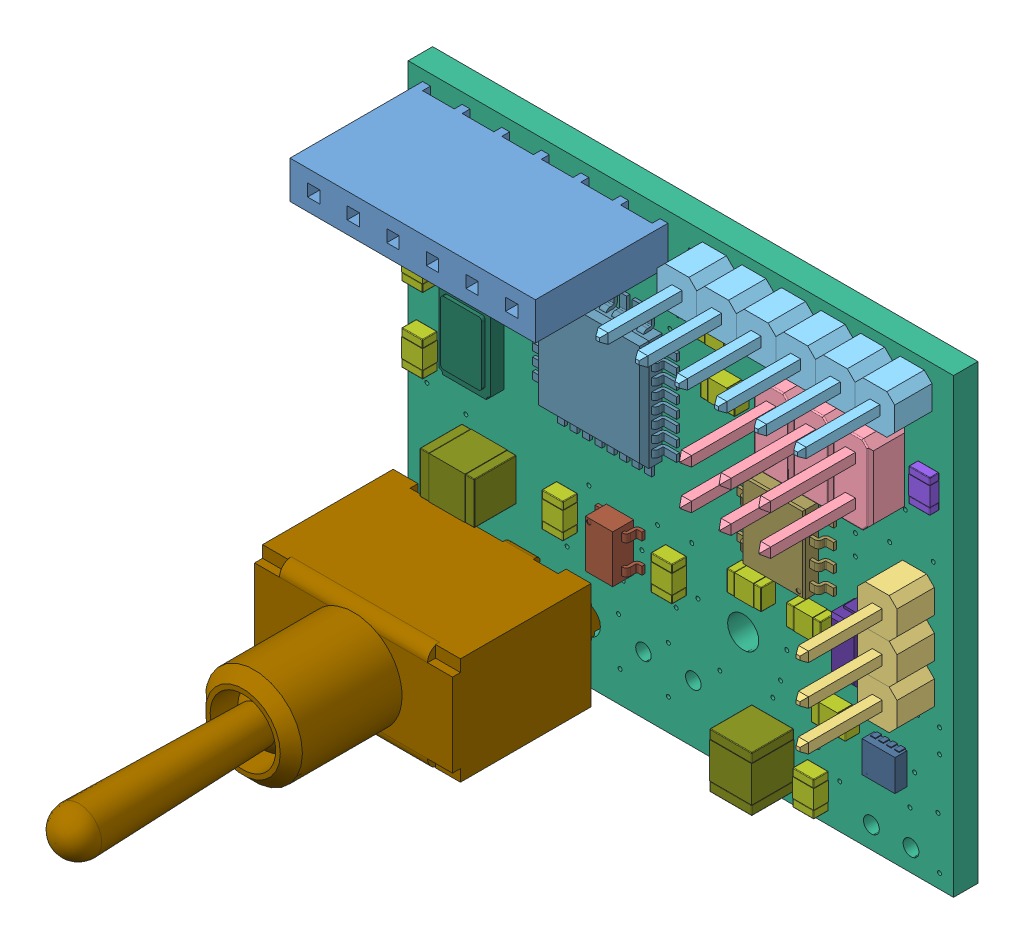
SolidWorks assembly vehicle.step, configuration Default. Lengths in mm.
Overall size (35 29 34.79).
43 component instances, 17 part files, 0 mates.
Components (placement in the parent):
- PCB Component.step-1: PCB Component.step [Default] at origin size (35 29 34.79)
  - HM-10.step-1: HM-10.step [Default] at (8.8 27.1 1.57) x (0 1 0) z (0 0 1) size (2.41 15.75 11.15)
    - _SSW-106-01-S-S_terminal.step-1: _SSW-106-01-S-S_terminal.step [Default] x (0 -1 0) z (-1 0 0) size (15.75 8.51 2.41)
    - _SSW-106-01-S-S_pin.step-1: _SSW-106-01-S-S_pin.step [Default] at (0 0 -2.6416) x (0 -1 0) z (-1 0 0) size (13.74 3.66 1.22)
  - MG90S.step-1: MG90S.step [Default] at (32.5 13.3 1.57) x (0 -1 0) z (0 0 1) size (7.62 2.54 10.67)
    - P(B,C)C01SAAN (1).step-1: P(B,C)C01SAAN (1).step [Default] at (-2.54 0 0) x (1 0 0) z (0 -1 0) size (2.54 10.67 2.54)
    - P(B,C)C01SAAN (1).step-2: P(B,C)C01SAAN (1).step [Default] x (-1 0 0) z (0 1 0) size (2.54 10.67 2.54)
    - P(B,C)C01SAAN (1).step-3: P(B,C)C01SAAN (1).step [Default] at (2.54 0 0) x (1 0 0) z (0 -1 0) size (2.54 10.67 2.54)
  - AVRISP.step-1: AVRISP.step [Default] at (28.2 22.4 1.57) size (7.62 5.08 11.29)
    - Dual TH withbump format.step-1: Dual TH withbump format.step [Default] at (-2.5 0 0) x (1 0 0) z (0 -1 0) size (2.54 11.29 5.08)
    - Dual TH withbump format.step-2: Dual TH withbump format.step [Default] at (0.04 0 0) x (-1 0 0) z (0 1 0) size (2.54 11.29 5.08)
    - Dual TH withbump format.step-3: Dual TH withbump format.step [Default] at (2.58 0 0) x (1 0 0) z (0 -1 0) size (2.54 11.29 5.08)
  - FTDI.step-1: FTDI.step [Default] at (26 27.1 1.57) size (15.24 2.54 10.67)
    - P(B,C)C01SAAN.step-1: P(B,C)C01SAAN.step [Default] at (-6.35 0 0) x (1 0 0) z (0 -1 0) size (2.54 10.67 2.54)
    - P(B,C)C01SAAN.step-2: P(B,C)C01SAAN.step [Default] at (-3.81 0 0) x (-1 0 0) z (0 1 0) size (2.54 10.67 2.54)
    - P(B,C)C01SAAN.step-3: P(B,C)C01SAAN.step [Default] at (-1.27 0 0) x (1 0 0) z (0 -1 0) size (2.54 10.67 2.54)
    - P(B,C)C01SAAN.step-4: P(B,C)C01SAAN.step [Default] at (1.27 0 0) x (-1 0 0) z (0 1 0) size (2.54 10.67 2.54)
    - P(B,C)C01SAAN.step-5: P(B,C)C01SAAN.step [Default] at (3.81 0 0) x (1 0 0) z (0 -1 0) size (2.54 10.67 2.54)
    - P(B,C)C01SAAN.step-6: P(B,C)C01SAAN.step [Default] at (6.35 0 0) x (-1 0 0) z (0 1 0) size (2.54 10.67 2.54)
  - Board.step-1: Board.step [Default] at origin size (35 29 1.57)
  - 1uF_25V.step-1: 1uF_25V.step [Default] at (1.2 13.8 1.57) x (0 -1 0) z (0 0 1) size (2.2 1.35 0.95)
  - 1uF_25V.step-2: 1uF_25V.step [Default] at (20.6 24.4 1.57) size (2.2 1.35 0.95)
  - 1uF_25V.step-3: 1uF_25V.step [Default] at (22.5 11.3 1.57) size (2.2 1.35 0.95)
  - 1uF_25V.step-4: 1uF_25V.step [Default] at (10.2 9.3 1.57) x (0 -1 0) z (0 0 1) size (2.2 1.35 0.95)
  - 1uF_25V.step-5: 1uF_25V.step [Default] at (17.2 9.3 1.57) x (0 -1 0) z (0 0 1) size (2.2 1.35 0.95)
  - 1uF_25V.step-6: 1uF_25V.step [Default] at (27.9 6.8 1.57) x (-1 0 0) z (0 0 1) size (2.2 1.35 0.95)
  - 1uF_25V.step-7: 1uF_25V.step [Default] at (26.3 1.9 1.57) x (0 1 0) z (0 0 1) size (2.2 1.35 0.95)
  - 10K.step-1: 10K.step [Default] at (33.4 22.1 1.57) x (0 1 0) z (0 0 1) size (2.1 1.35 0.6)
  - 5A_28V.step-1: 5A_28V.step [Default] at (6.7 3.7 1.57) x (0 1 0) z (0 0 1) size (7.08 12.71 34.79)
  - DRV8838D 1.8A.step-1: DRV8838D 1.8A.step [Default] at (31 5.7 1.57) x (0 1 0) z (0 0 1) size (2.11 2.11 0.81)
  - MCP1802T-500 300mA_5V.step-1: MCP1802T-500 300mA_5V.step [Default] at (13.7 9.3 1.57) size (3 3.05 1.45)
  - BD60GC0WEFJ 1A_6V.step-1: BD60GC0WEFJ 1A_6V.step [Default] at (24.4 15.2 1.57) x (-1 0 0) z (0 0 1) size (6.2 5 1)
  - 1uF_25V.step-8: 1uF_25V.step [Default] at (26.3 11.3 1.57) x (-1 0 0) z (0 0 1) size (2.2 1.35 0.95)
  - 1uF_25V.step-9: 1uF_25V.step [Default] at (1.2 18.6 1.57) x (0 1 0) z (0 0 1) size (2.2 1.35 0.95)
  - 1uF_25V.step-10: 1uF_25V.step [Default] at (4.8 20.3 1.57) x (-1 0 0) z (0 0 1) size (2.2 1.35 0.95)
  - 1uF_25V.step-11: 1uF_25V.step [Default] at (4.8 22.5 1.57) x (-1 0 0) z (0 0 1) size (2.2 1.35 0.95)
  - 2PT_GND_TIE.step-1: 2PT_GND_TIE.step [Default] at (19.1 1.8 0) x (-1 0 0) z (0 0 -1) size (1.68 0.41 0.1)
  - ATMEGA328p.step-1: ATMEGA328p.step [Default] at (12.8 18.5 1.57) size (9.25 9.25 1.2)
  - 16 MHz.step-1: 16 MHz.step [Default] at (4.5 16.1 1.57) x (0 -1 0) z (0 0 1) size (5.1 3.3 1.1)
  - 100uF_16V.step-1: 100uF_16V.step [Default] at (23.4 2.5 1.57) x (0 1 0) z (0 0 1) size (3.5 2.7 2.7)
  - 100uF_16V.step-2: 100uF_16V.step [Default] at (5.2 9.2 1.57) x (-1 0 0) z (0 0 1) size (3.5 2.7 2.7)
  - 10uF_16V.step-1: 10uF_16V.step [Default] at (29.7 11.9 1.57) x (0 -1 0) z (0 0 1) size (3.7 1.8 1.8)
  - 1uF_25V.step-12: 1uF_25V.step [Default] at (20.8 21.3 1.57) size (2.2 1.35 0.95)
